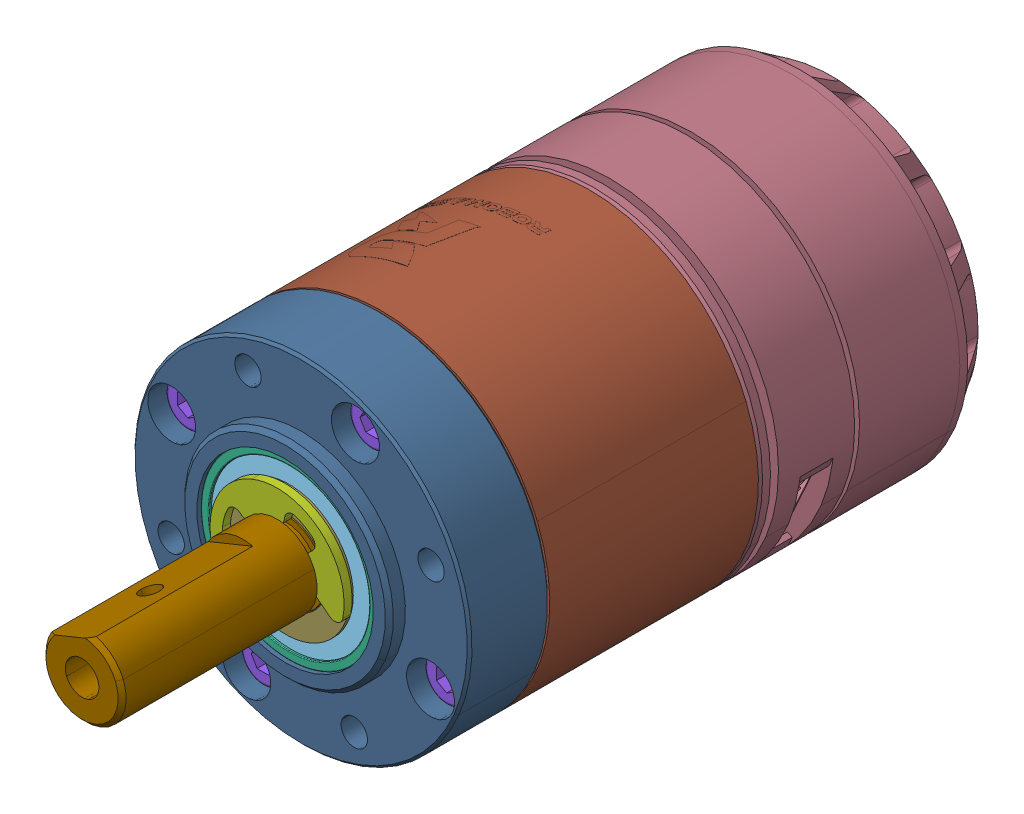
SolidWorks assembly RoboMaster M3508直流无刷减速电, configuration 默认. Lengths in mm.
Overall size (54.98 54.98 98.4).
32 component instances, 17 part files, 0 mates.
Components (placement in the parent):
- RoboMaster M3508直流无刷减速电.stp-1: RoboMaster M3508直流无刷减速电.stp [默认] at origin size (91.88 185.59 98.4)
  - 4_ASM.stp-1: 4_ASM.stp [默认] at (-1.7887 18.2683 39.841) x (-0.923508 0.383579 0) z (0.383579 0.923508 0) size (13.16 4.26 21.29)
    - __-__10_1_.stp-1: __-__10_1_.stp [默认] at origin size (2.4 2.3 2.24)
    - __-__10_3_.stp-1: __-__10_3_.stp [默认] at origin size (2.4 2.3 2.24)
    - __-__10_2_.stp-1: __-__10_2_.stp [默认] at origin size (2.4 2.3 2.24)
    - __-__20.stp-1: __-__20.stp [默认] at origin size (5.92 4.26 12.18)
  - 5_ASM.stp-1: 5_ASM.stp [默认] at (56.824 -105.7062 43.091) x (0.954008 0.299781 0) z (-0.299781 0.954008 0) size (14.1 10.78 139.15)
    - 15.stp-1: 15.stp [默认] at (-14.7519 0 22.9937) x (-1 0 0) z (0 0 -1) size (2.5 2.5 100) (hidden)
    - 15.stp-2: 15.stp [默认] at (-18.7519 0 22.9937) x (0 1 0) z (0 0 -1) size (2.5 2.5 100) (hidden)
    - 15.stp-3: 15.stp [默认] at (-22.7519 0 22.9937) x (-1 0 0) z (0 0 -1) size (2.5 2.5 100) (hidden)
    - 20.stp-1: 20.stp [默认] at (-1.9783 -5.4851 11.3276) x (1 0 0) z (0 0 -1) size (11.94 4.93 6.5) (hidden)
    - 19.stp-1: 19.stp [默认] at origin size (12.31 5.48 13.41) (hidden)
  - 2_ASM.stp-1: 2_ASM.stp [默认] at (-1.7887 18.2683 50.441) x (-0.378508 0.925598 0) z (0.925598 0.378508 0) size (59.4 67.29 59.4)
    - 26_ASM.stp-1: 26_ASM.stp [默认] at (0 34.5 0) x (-0.381788 0 0.92425) z (-0.92425 0 -0.381788) size (22 6 22)
      - 28.stp-1: 28.stp [默认] at (0 2.5 0) size (20 0.2 20)
      - 27.stp-1: 27.stp [默认] at origin size (22 6 22)
      - 28.stp-2: 28.stp [默认] at (0 -2.7 0) size (20 0.2 20)
    - 26_ASM.stp-2: 26_ASM.stp [默认] at (0 27 0) x (-0.381788 0 0.92425) z (-0.92425 0 -0.381788) size (22 6 22)
      - 28.stp-1: 28.stp [默认] at (0 2.5 0) size (20 0.2 20)
      - 27.stp-1: 27.stp [默认] at origin size (22 6 22)
      - 28.stp-2: 28.stp [默认] at (0 -2.7 0) size (20 0.2 20)
    - 25.stp-1: 25.stp [默认] at (0 38.5 0) x (0 0 1) z (-1 0 0) size (16.7 1 13.43)
    - 18.stp-1: 18.stp [默认] at (-12.3744 22 -12.3744) x (0.381788 0 -0.92425) z (0.92425 0 0.381788) size (5.5 37.99 5.5)
    - 17.stp-1: 17.stp [默认] at (0 19.3 0) x (-1 0 0) z (0 0 -1) size (26 44 26)
    - 16.stp-1: 16.stp [默认] at (0 31 0) x (-0.707107 0 0.707107) z (0 1 0) size (42 42 14)
    - 18.stp-2: 18.stp [默认] at (12.3744 22 -12.3744) x (0.92425 0 0.381788) z (-0.381788 0 0.92425) size (5.5 37.99 5.5)
    - 23.stp-1: 23.stp [默认] at origin size (42.01 26 42)
    - 18.stp-3: 18.stp [默认] at (12.3744 22 12.3744) x (-0.381788 0 0.92425) z (-0.92425 0 -0.381788) size (5.5 37.99 5.5)
    - 18.stp-4: 18.stp [默认] at (-12.3744 22 12.3744) x (-0.92425 0 -0.381788) z (0.381788 0 -0.92425) size (5.5 37.99 5.5)
    - 24.stp-1: 24.stp [默认] at (0 37.71 0) x (0 1 0) z (0.381788 0 -0.92425) size (0.42 16 16)
  - 1_1.stp-1: 1_1.stp [默认] at (-1.7887 18.2683 48.441) x (0.923508 -0.383579 0) z (0 0 1) size (42 42 43.4)
  - 3.stp-1: 3.stp [默认] at (4.5067 -1.7659 43.091) x (0.299781 -0.954008 0) z (0.954008 0.299781 0) size (5.77 4 14.5) (hidden)
